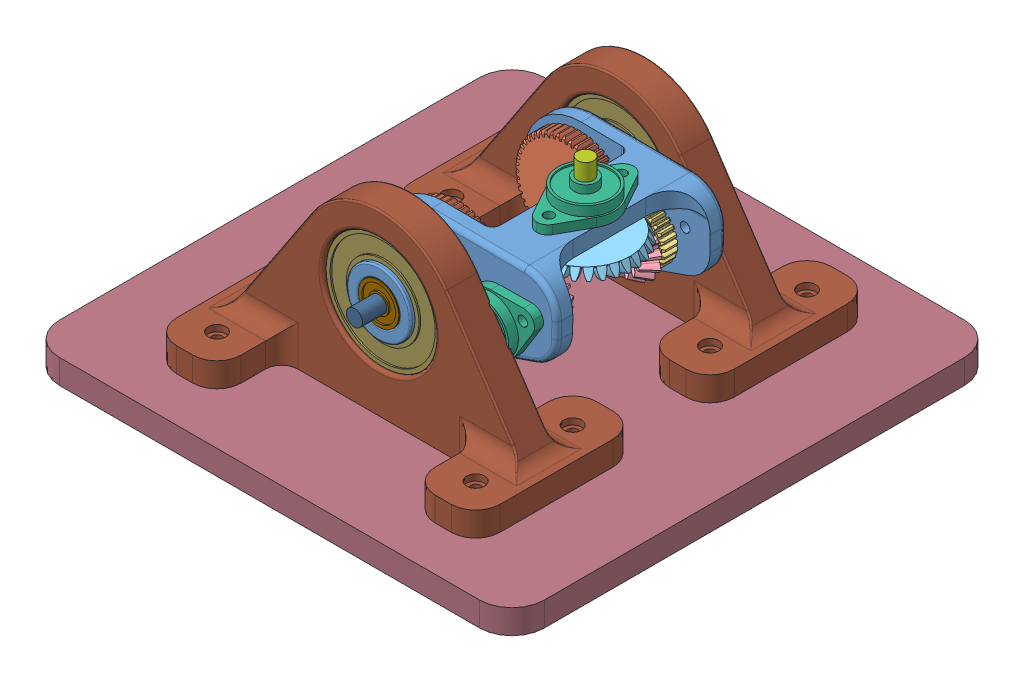
SolidWorks assembly ASSEMBLY Full Design 4th Attempt - Holder Frame Design, configuration Default. Lengths in mm.
Overall size (300 144.17 300).
25 component instances, 13 part files, 62 mates.
Components (placement in the parent):
- Main Case-1: Main Case [Default] at (-15.1172 135.8372 30.5077) x (0.999965 -0.008399 0) z (0 0 1) size (115 70 165)
- Secondary Big Spur Gear-1: Secondary Big Spur Gear [Default] at (-15.1172 135.8372 45.5077) x (0.223812 0.974632 0) z (0 0 1) size (62.4 62.32 10)
- Secondary Big Spur Gear-2: Secondary Big Spur Gear [Default] at (-15.1172 135.8372 120.5077) x (-0.440646 0.897681 0) z (0 0 1) size (62.4 62.32 10)
- Main Spur Gear - Copy-1: Main Spur Gear - Copy [Default] at (29.8812 135.4592 120.5077) x (-0.557244 0.830349 0) z (0 0 1) size (32.38 32.33 10)
- Main Spur Gear - Copy-2: Main Spur Gear - Copy [Default] at (29.8812 135.4592 45.5077) x (-0.968851 0.247643 0) z (0 0 1) size (32.38 32.33 10)
- Secondary Bevel Gear-1: Secondary Bevel Gear [Default] at (29.8812 135.4592 53.1298) x (0.968851 -0.247643 0) z (-0.247643 -0.968851 0) size (38.46 39.84 38.26)
- Secondary Bevel Gear-2: Secondary Bevel Gear [Default] at (29.8812 135.4592 112.8856) x (-0.557244 0.830349 0) z (-0.830349 -0.557244 0) size (38.46 39.84 38.26)
- Secondary Main Bevel Gear-1: Secondary Main Bevel Gear [Default] at (30.0267 152.7791 83.0077) x (-0.999724 0.008397 -0.02196) z (-0.021959 0.000184 0.999759) size (61.95 69.28 62)
- Main Slewing Bearing-1: Main Slewing Bearing [Default] at (30.1752 170.458 83.0077) x (0 0 -1) z (0.999965 -0.008399 0) size (60 15.5 36)
- Secondary Gear Shaft-1: Secondary Gear Shaft [Default] at (30.3944 196.5599 83.0077) x (0.999724 -0.008397 0.02196) z (0.021959 -0.000184 -0.999759) size (10 46 10)
- Secondary Gear Shaft Horizontal-1: Secondary Gear Shaft Horizontal [Default] at (29.8812 135.4592 151.977) x (0.557244 -0.830349 0) z (0.830349 0.557244 0) size (10 46 10)
- Secondary Gear Shaft Horizontal-3: Secondary Gear Shaft Horizontal [Default] at (29.8812 135.4592 14.0383) x (-0.968851 0.247643 0) z (0.247643 0.968851 0) size (10 46 10)
- Main Slewing Bearing-2: Main Slewing Bearing [Default] at (29.8812 135.4592 30.5077) x (0.870194 0.492709 0) z (-0.492709 0.870194 0) size (60 15.5 36)
- Main Slewing Bearing-3: Main Slewing Bearing [Default] at (29.8812 135.4592 135.5077) x (0.870194 0.492709 0) z (0.492709 -0.870194 0) size (60 15.5 36)
- Main Bearing-1: Main Bearing [Default] at (-15.1172 135.8372 130.5077) size (25 25 10)
- Main Bearing-2: Main Bearing [Default] at (-15.1172 135.8372 35.5077) size (25 25 10)
- Secondary Gear Shaft Horizontal Back-1: Secondary Gear Shaft Horizontal Back [Default] at (-15.1172 135.8372 -14.4923) x (0.223812 0.974632 0) z (0.974632 -0.223812 0) size (10 65 10)
- Secondary Gear Shaft Horizontal Back-2: Secondary Gear Shaft Horizontal Back [Default] at (-15.1172 135.8372 180.5077) x (0.440646 -0.897681 0) z (0.897681 0.440646 0) size (10 65 10)
- Main Bearing-3: Main Bearing [Default] at (-15.1172 135.8372 160.5077) size (25 25 10)
- Main Bearing-4: Main Bearing [Default] at (-15.1172 135.8372 5.5077) x (0.957621 -0.288033 0) z (0 0 1) size (25 25 10)
- Main Holder-1: Main Holder [Default] at (-15.1172 135.8372 155.5077) size (200 110 100)
- Main Holder-2: Main Holder [Default] at (-15.1172 135.8372 10.5077) size (200 110 100)
- Main Bearing Big-1: Main Bearing Big [Default] at (-15.1172 135.8372 155.5077) size (70 70 15)
- Main Bearing Big-2: Main Bearing Big [Default] at (-15.1172 135.8372 10.5077) size (70 70 15)
- Bottom Plate-1: Bottom Plate [Default] at (-15.1172 60.8372 83.0077) x (0 0 1) z (-1 0 0) size (300 15 300)
Mates (geometry in assembly coordinates):
- Concentric1: concentric aligned: cylinder of Main Case-1 through (-15.1172 135.8372 125.5077) axis (0 0 1) radius 12.5; cylinder of Secondary Big Spur Gear-2 through (-15.1172 135.8372 115.5077) axis (0 0 1) radius 5
- Coincident1: coincident anti-aligned: plane of Main Case-1 through (-15.1172 135.8372 125.5077) normal (0 0 -1); plane of Secondary Big Spur Gear-2 through (-15.1172 135.8372 125.5077) normal (0 0 1)
- Concentric2: concentric anti-aligned: cylinder of Main Case-1 through (-15.1172 135.8372 40.5077) axis (0 0 -1) radius 12.5; cylinder of Secondary Big Spur Gear-1 through (-15.1172 135.8372 40.5077) axis (0 0 1) radius 5
- Coincident2: coincident anti-aligned: plane of Main Case-1 through (-15.1172 135.8372 40.5077) normal (0 0 1); plane of Secondary Big Spur Gear-1 through (-15.1172 135.8372 40.5077) normal (0 0 -1)
- Concentric3: concentric anti-aligned: cylinder of Main Case-1 through (29.8812 135.4592 40.5077) axis (0 0 -1) radius 5; cylinder of Main Spur Gear - Copy-2 through (29.8812 135.4592 40.5077) axis (0 0 1) radius 5
- Coincident3: coincident anti-aligned: plane of Main Case-1 through (-15.1172 135.8372 40.5077) normal (0 0 1); plane of Main Spur Gear - Copy-2 through (29.8812 135.4592 40.5077) normal (0 0 -1)
- GearMate1: gear = 60 : 30 mm: circle of Main Spur Gear - Copy-2; circle of Secondary Big Spur Gear-1
- Concentric5: concentric aligned: cylinder of Main Case-1 through (29.8812 135.4592 125.5077) axis (0 0 1) radius 5; cylinder of Main Spur Gear - Copy-1 through (29.8812 135.4592 115.5077) axis (0 0 1) radius 5
- Coincident4: coincident anti-aligned: plane of Main Case-1 through (-15.1172 135.8372 125.5077) normal (0 0 -1); plane of Main Spur Gear - Copy-1 through (29.8812 135.4592 125.5077) normal (0 0 1)
- GearMate2: gear = 60 : 30 mm: circle of Main Spur Gear - Copy-1; circle of Secondary Big Spur Gear-2
- Concentric7: concentric aligned: cylinder of Main Case-1 through (29.8812 135.4592 40.5077) axis (0 0 -1) radius 5; cylinder of Secondary Bevel Gear-1 through (29.8812 135.4592 62.5883) axis (0 0 -1) radius 5
- Coincident5: coincident aligned: plane of Main Spur Gear - Copy-2 through (30.0854 128.182 40.5077) normal (0.247643 0.968851 0); plane of Secondary Bevel Gear-1 through (26.21 129.1726 62.5883) normal (0.247643 0.968851 0)
- Concentric8: concentric aligned: cylinder of Main Spur Gear - Copy-1 through (29.8812 135.4592 115.5077) axis (0 0 1) radius 5; cylinder of Secondary Bevel Gear-2 through (29.8812 135.4592 103.4271) axis (0 0 1) radius 5
- Coincident6: coincident aligned: plane of Main Spur Gear - Copy-1 through (25.1833 129.8978 115.5077) normal (0.830349 0.557244 0); plane of Secondary Bevel Gear-2 through (25.1833 129.8978 103.4271) normal (0.830349 0.557244 0)
- Concentric9: concentric aligned: cylinder of Main Case-1 through (29.5872 100.4605 83.0077) axis (0.008399 0.999965 0) radius 5; cylinder of Secondary Main Bevel Gear-1 through (29.9744 146.5548 83.0077) axis (0.008399 0.999965 0) radius 5
- Coincident7: coincident: point of Secondary Bevel Gear-1; point of Secondary Main Bevel Gear-1
- Coincident8: coincident: line of Secondary Bevel Gear-2 through (29.8812 135.4592 83.0077) axis (0.278622 -0.415174 0.866025)
- GearMate3: gear = 34.5 : 60 mm: circle of Secondary Main Bevel Gear-1; circle of Secondary Bevel Gear-1
- GearMate4: gear = 60 : 34.5 mm: circle of Secondary Bevel Gear-2; circle of Secondary Main Bevel Gear-1
- Concentric11: concentric aligned: cylinder of Main Case-1 through (29.5872 100.4605 83.0077) axis (0.008399 0.999965 0) radius 5; cylinder of Main Slewing Bearing-1 through (30.1752 170.458 83.0077) axis (0.008399 0.999965 0) radius 5
- Concentric12: concentric anti-aligned: cylinder of Main Case-1 through (30.1752 170.458 60.5077) axis (0.008399 0.999965 0) radius 3; cylinder of Main Slewing Bearing-1 through (30.2214 175.9578 60.5077) axis (-0.008399 -0.999965 0) radius 3
- Coincident9: coincident anti-aligned: plane of Main Case-1 through (-14.8232 170.8359 40.5077) normal (0.008399 0.999965 0); plane of Main Slewing Bearing-1 through (30.1752 170.458 83.0077) normal (-0.008399 -0.999965 0)
- Concentric13: concentric aligned: cylinder of Main Slewing Bearing-1 through (30.1752 170.458 83.0077) axis (0.008399 0.999965 0) radius 5; cylinder of Secondary Gear Shaft-1 through (30.0081 150.5615 83.0077) axis (0.008399 0.999965 0) radius 5
- Coincident10: coincident aligned: plane of Secondary Main Bevel Gear-1 through (49.7552 150.3956 83.4415) normal (-0.008399 -0.999965 0); plane of Secondary Gear Shaft-1 through (30.0081 150.5615 83.0077) normal (-0.008399 -0.999965 0)
- Coincident11: coincident aligned: plane of Secondary Main Bevel Gear-1 through (31.8732 146.5388 87.6331) normal (-0.999724 0.008397 -0.02196); plane of Secondary Gear Shaft-1 through (32.0256 160.5449 86.0509) normal (-0.999724 0.008397 -0.02196)
- Concentric14: concentric aligned: cylinder of Secondary Bevel Gear-1 through (29.8812 135.4592 62.5883) axis (0 0 -1) radius 5; cylinder of Secondary Gear Shaft Horizontal-3 through (29.8812 135.4592 60.0383) axis (0 0 -1) radius 5
- Coincident12: coincident aligned: plane of Secondary Bevel Gear-1 through (20.9094 137.7525 60.0383) normal (0 0 1); plane of Secondary Gear Shaft Horizontal-3 through (29.8812 135.4592 60.0383) normal (0 0 1)
- Coincident15: coincident aligned: plane of Secondary Bevel Gear-1 through (26.8087 131.5147 62.5883) normal (0.968851 -0.247643 0); plane of Secondary Gear Shaft Horizontal-3 through (27.2006 133.048 50.0383) normal (0.968851 -0.247643 0)
- Concentric15: concentric aligned: cylinder of Secondary Bevel Gear-2 through (29.8812 135.4592 103.4271) axis (0 0 1) radius 5; cylinder of Secondary Gear Shaft Horizontal-1 through (29.8812 135.4592 105.977) axis (0 0 1) radius 5
- Coincident16: coincident aligned: plane of Secondary Bevel Gear-2 through (35.0414 127.77 105.977) normal (0 0 -1); plane of Secondary Gear Shaft Horizontal-1 through (29.8812 135.4592 105.977) normal (0 0 -1)
- Coincident17: coincident aligned: plane of Secondary Bevel Gear-2 through (27.1906 131.2449 103.4271) normal (-0.557244 0.830349 0); plane of Secondary Gear Shaft Horizontal-1 through (28.5046 132.1268 115.977) normal (-0.557244 0.830349 0)
- Concentric16: concentric aligned: cylinder of Secondary Gear Shaft Horizontal-3 through (29.8812 135.4592 60.0383) axis (0 0 -1) radius 5; cylinder of Main Slewing Bearing-2 through (29.8812 135.4592 30.5077) axis (0 0 -1) radius 5
- Coincident18: coincident anti-aligned: plane of Main Case-1 through (-15.1172 135.8372 30.5077) normal (0 0 -1); plane of Main Slewing Bearing-2 through (29.8812 135.4592 30.5077) normal (0 0 1)
- Concentric17: concentric anti-aligned: cylinder of Main Case-1 through (49.4606 146.5452 135.5077) axis (0 0 -1) radius 3; cylinder of Main Slewing Bearing-2 through (49.4606 146.5452 25.0077) axis (0 0 1) radius 3
- Concentric18: concentric aligned: cylinder of Secondary Gear Shaft Horizontal-1 through (29.8812 135.4592 105.977) axis (0 0 1) radius 5; cylinder of Main Slewing Bearing-3 through (29.8812 135.4592 135.5077) axis (0 0 1) radius 5
- Concentric19: concentric aligned: cylinder of Main Case-1 through (49.4606 146.5452 135.5077) axis (0 0 -1) radius 3; cylinder of Main Slewing Bearing-3 through (49.4606 146.5452 141.0077) axis (0 0 -1) radius 3
- Coincident19: coincident anti-aligned: plane of Main Case-1 through (-15.1172 135.8372 135.5077) normal (0 0 1); plane of Main Slewing Bearing-3 through (29.8812 135.4592 135.5077) normal (0 0 -1)
- Concentric20: concentric anti-aligned: cylinder of Main Case-1 through (-15.1172 135.8372 125.5077) axis (0 0 1) radius 12.5; cylinder of Main Bearing-1 through (-15.1172 135.8372 135.5077) axis (0 0 -1) radius 12.5
- Coincident20: coincident aligned: plane of Main Case-1 through (-15.1172 135.8372 135.5077) normal (0 0 1); plane of Main Bearing-1 through (-15.1172 135.8372 135.5077) normal (0 0 1)
- Concentric21: concentric aligned: cylinder of Main Case-1 through (-15.1172 135.8372 40.5077) axis (0 0 -1) radius 12.5; cylinder of Main Bearing-2 through (-15.1172 135.8372 40.5077) axis (0 0 -1) radius 5
- Coincident21: coincident aligned: plane of Main Case-1 through (-15.1172 135.8372 30.5077) normal (0 0 -1); plane of Main Bearing-2 through (-15.1172 135.8372 30.5077) normal (0 0 -1)
- Concentric22: concentric aligned: cylinder of Main Bearing-2 through (-15.1172 135.8372 40.5077) axis (0 0 -1) radius 5; cylinder of Secondary Gear Shaft Horizontal Back-1 through (-15.1172 135.8372 50.5077) axis (0 0 -1) radius 5
- Coincident22: coincident aligned: plane of Secondary Big Spur Gear-1 through (-15.1172 135.8372 50.5077) normal (0 0 1); plane of Secondary Gear Shaft Horizontal Back-1 through (-15.1172 135.8372 50.5077) normal (0 0 1)
- Coincident23: coincident aligned: plane of Secondary Big Spur Gear-1 through (-20.0312 134.9136 40.5077) normal (0.223812 0.974632 0); plane of Secondary Gear Shaft Horizontal Back-1 through (-18.4887 134.5594 40.5077) normal (0.223812 0.974632 0)
- Concentric23: concentric anti-aligned: cylinder of Main Bearing-1 through (-15.1172 135.8372 135.5077) axis (0 0 -1) radius 5; cylinder of Secondary Gear Shaft Horizontal Back-2 through (-15.1172 135.8372 115.5077) axis (0 0 1) radius 5
- Coincident24: coincident aligned: plane of Secondary Big Spur Gear-2 through (-15.1172 135.8372 115.5077) normal (0 0 -1); plane of Secondary Gear Shaft Horizontal Back-2 through (-15.1172 135.8372 115.5077) normal (0 0 -1)
- Coincident25: coincident aligned: plane of Secondary Big Spur Gear-2 through (-18.3496 132.0225 115.5077) normal (-0.440646 0.897681 0); plane of Secondary Gear Shaft Horizontal Back-2 through (-16.929 132.7199 125.5077) normal (-0.440646 0.897681 0)
- Concentric24: concentric anti-aligned: cylinder of Main Case-1 through (-15.1172 135.8372 125.5077) axis (0 0 1) radius 12.5; cylinder of Main Bearing-3 through (-15.1172 135.8372 165.5077) axis (0 0 -1) radius 12.5
- Coincident26: coincident aligned: plane of Main Case-1 through (-15.1172 135.8372 165.5077) normal (0 0 1); plane of Main Bearing-3 through (-15.1172 135.8372 165.5077) normal (0 0 1)
- Concentric25: concentric aligned: cylinder of Main Case-1 through (-15.1172 135.8372 40.5077) axis (0 0 -1) radius 12.5; cylinder of Main Bearing-4 through (-15.1172 135.8372 10.5077) axis (0 0 -1) radius 12.5
- Coincident27: coincident aligned: plane of Main Case-1 through (-15.1172 135.8372 0.5077) normal (0 0 -1); plane of Main Bearing-4 through (-15.1172 135.8372 0.5077) normal (0 0 -1)
- Concentric26: concentric aligned: cylinder of Main Holder-1 through (-15.1172 135.8372 205.5077) axis (0 0 -1) radius 35; cylinder of Main Bearing Big-1 through (-15.1172 135.8372 163.0077) axis (0 0 -1) radius 35
- Coincident28: coincident aligned: plane of Main Holder-1 through (-15.1172 135.8372 155.5077) normal (0 0 1); plane of Main Bearing Big-1 through (-15.1172 135.8372 155.5077) normal (0 0 1)
- Coincident29: coincident aligned: plane of Main Holder-2 through (-15.1172 135.8372 10.5077) normal (0 0 1); plane of Main Bearing Big-2 through (-15.1172 135.8372 10.5077) normal (0 0 1)
- Concentric27: concentric aligned: cylinder of Main Holder-2 through (-15.1172 135.8372 60.5077) axis (0 0 -1) radius 35; cylinder of Main Bearing Big-2 through (-15.1172 135.8372 18.0077) axis (0 0 -1) radius 35
- Concentric28: concentric aligned: cylinder of Main Case-1 through (-15.1172 135.8372 165.5077) axis (0 0 -1) radius 20; cylinder of Main Bearing Big-1 through (-15.1172 135.8372 163.0077) axis (0 0 -1) radius 20
- Concentric29: concentric anti-aligned: cylinder of Main Case-1 through (-15.1172 135.8372 0.5077) axis (0 0 1) radius 20; cylinder of Main Bearing Big-2 through (-15.1172 135.8372 18.0077) axis (0 0 -1) radius 20
- Coincident30: coincident aligned: plane of Main Case-1 through (-15.1172 135.8372 165.5077) normal (0 0 1); plane of Main Holder-1 through (-15.1172 135.8372 165.5077) normal (0 0 1)
- Coincident31: coincident aligned: plane of Main Case-1 through (-15.1172 135.8372 0.5077) normal (0 0 -1); plane of Main Holder-2 through (-15.1172 135.8372 0.5077) normal (0 0 -1)
- Concentric30: concentric aligned: cylinder of Main Holder-2 through (64.8828 90.8372 -19.4923) axis (0 1 0) radius 3.2; cylinder of Bottom Plate-1 through (64.8828 75.8372 -19.4923) axis (0 1 0) radius 3
- Coincident32: coincident anti-aligned: plane of Main Holder-2 through (-115.1172 75.8372 20.5077) normal (0 -1 0); plane of Bottom Plate-1 through (-15.1172 75.8372 83.0077) normal (0 1 0)
- Concentric32: concentric aligned: cylinder of Main Holder-1 through (64.8828 90.8372 185.5077) axis (0 1 0) radius 3.2; circle of Bottom Plate-1
